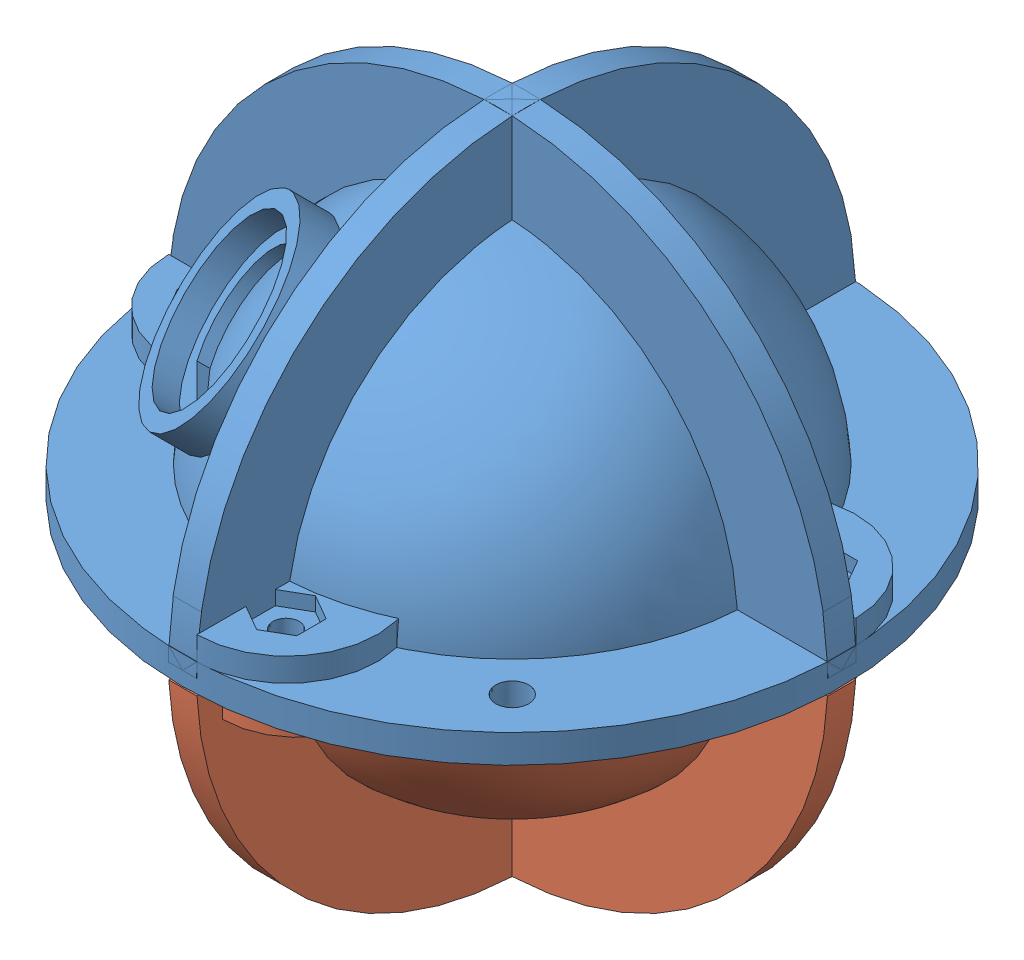
SolidWorks assembly Assem1, configuration Default. Lengths in mm.
Overall size (70 70 70).
2 component instances, 2 part files, 4 mates.
Components (placement in the parent):
- enclosure_half_one_VOLUME-1: enclosure_half_one_VOLUME [Default] at origin size (70 59.29 70)
- enclosure_half_two-1: enclosure_half_two [Default] x (1 0 0) z (0 0 -1) size (69.92 35 69.92)
Mates (geometry in assembly coordinates):
- Coincident2: coordinate: point of enclosure_half_one_VOLUME-1
- Concentric1: concentric: sphere of enclosure_half_one_VOLUME-1; sphere of enclosure_half_two-1
- Parallel1: parallel: plane of enclosure_half_one_VOLUME-1 through (0 -1.5 0) normal (0 -1 0); plane of enclosure_half_two-1 through (-21.8051 -1.65 10.6911) normal (0 1 0)
- Coincident4: coincident aligned: plane of enclosure_half_one_VOLUME-1 through (0 0 0) normal (1 0 0); plane of enclosure_half_two-1 through (0 0 0) normal (1 0 0)
